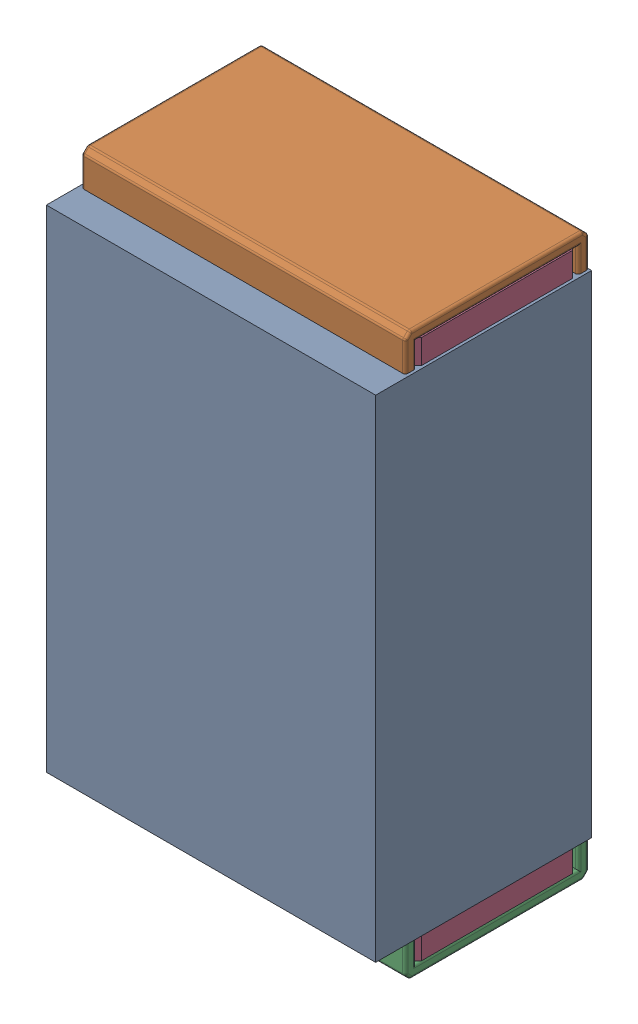
SolidWorks assembly R9, configuration Default. Lengths in mm.
Overall size (0.61 1.04 0.4).
3 component instances, 2 part files, 0 mates.
Components (placement in the parent):
- 1088881848-1: 1088881848 [Default] at (10.25 34.65 0) size (0.61 0.91 0.4)
  - Extruded-1-1: Extruded-1 [Default] at origin size (0.61 0.91 0.4)
- R0402-1: R0402 [Default] at (10.25 34.6501 0) x (0 1 0) z (1 0 0) size (1.04 0.34 0.6)
